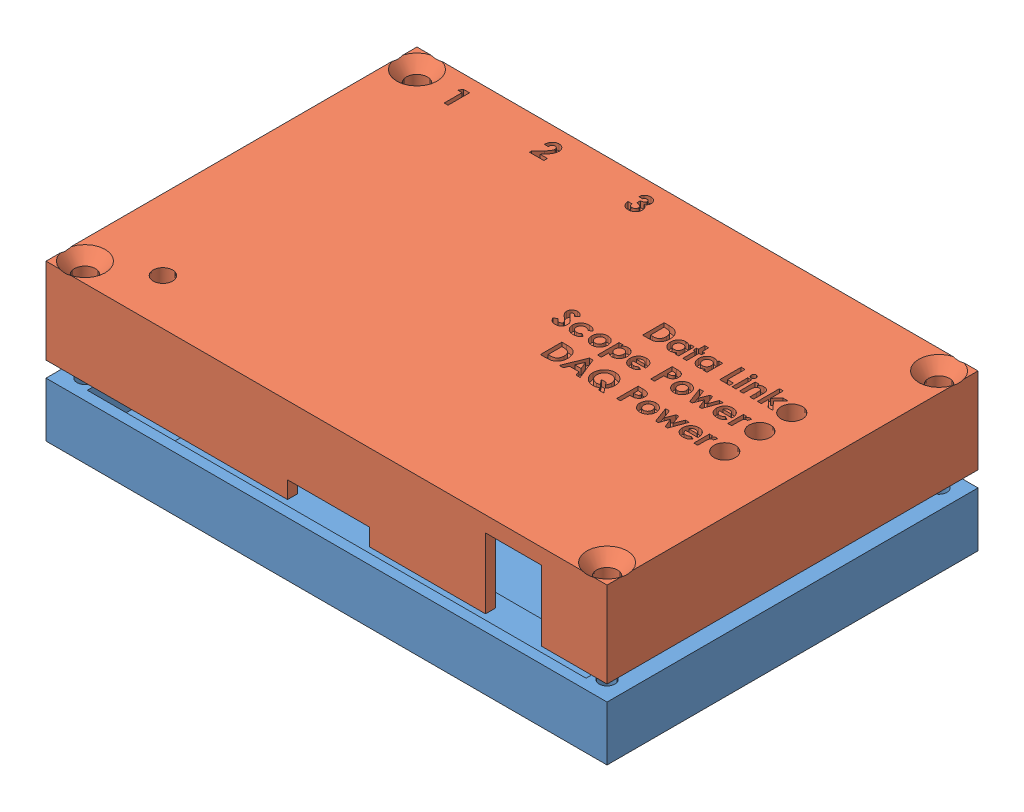
SolidWorks assembly DAQ Boz, configuration Default. Lengths in mm.
Overall size (91.44 25.59 60.45).
2 component instances, 2 part files, 3 mates.
Components (placement in the parent):
- Bottom-1: Bottom [Default] at (-11.2026 -6.463 7.2824) size (91.44 8.89 60.45)
- Top-1: Top [Default] at (-11.2026 4.967 7.2824) size (91.44 14.16 60.45)
Mates (geometry in assembly coordinates):
- Concentric1: concentric anti-aligned: cylinder of Bottom-1 through (-53.7476 -6.463 34.3334) axis (0 1 0) radius 1.2891; cylinder of Top-1 through (-53.7476 18.937 34.3334) axis (0 -1 0) radius 1.7145
- Concentric2: concentric anti-aligned: cylinder of Bottom-1 through (-53.7476 -6.463 -19.7686) axis (0 1 0) radius 1.2891; cylinder of Top-1 through (-53.7476 18.937 -19.7686) axis (0 -1 0) radius 1.7145
- Distance1: distance = 2.54 mm anti-aligned: plane of Bottom-1 through (-11.2026 2.427 7.2824) normal (0 1 0); plane of Top-1 through (-11.2026 4.967 7.2824) normal (0 -1 0)
